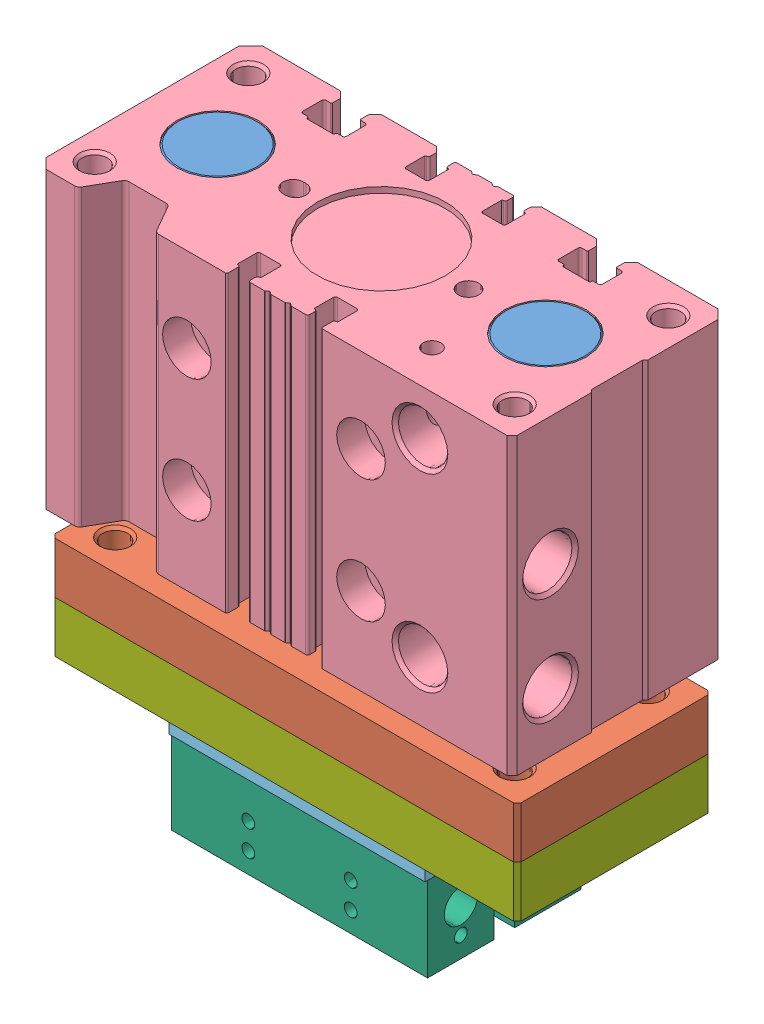
SolidWorks assembly SEALER, configuration Default. Lengths in mm.
Overall size (93 107 42).
11 component instances, 7 part files, 19 mates.
Components (placement in the parent):
- MTCM-25X20-S-T.stp-1: MTCM-25X20-S-T.stp [Default] at (46.5 -57.5 21) x (0 1 0) z (1 0 0) size (73.5 42 93)
  - MTCM-25X20-S-T-0_guide_shaft.stp-1: MTCM-25X20-S-T-0_guide_shaft.stp [Default] at (-8 0 32) size (72.56 16 16)
  - MTCM-25X20-S-T-0_guide_shaft.stp-2: MTCM-25X20-S-T-0_guide_shaft.stp [Default] at (-8 0 -32) size (72.56 16 16)
  - MTCM-25X20-S-T_plate.stp-1: MTCM-25X20-S-T_plate.stp [Default] at (-6 0 0) size (10 38 91)
  - MTCM-25X20-S-T-0_guide_rod.stp-1: MTCM-25X20-S-T-0_guide_rod.stp [Default] at (-8 0 0) size (68.06 25 25)
  - MTCM-25X20-S-T-0_body.stp-1: MTCM-25X20-S-T-0_body.stp [Default] at origin size (57.5 42 93)
- INSULATION-1: INSULATION [Default] at (46 -86 30) x (1 0 0) z (0 -1 0) size (50 14 5)
- INSULATION-2: INSULATION [Default] at (46 -86 13) x (1 0 0) z (0 -1 0) size (50 14 5)
- HEATER-1: HEATER [Default] at (46 -96.75 13) x (-1 0 0) z (0 0 -1) size (50 18.5 13)
- HEATER-2: HEATER [Default] at (46 -96.75 30) size (50 18.5 13)
- Mounting plate-1: Mounting plate [Default] at (93 -73.5 42) x (-1 0 0) z (0 -1 0) size (91 38 10)
Mates (geometry in assembly coordinates):
- Concentric81: concentric anti-aligned: cylinder of INSULATION-2 through (56 -88.5 13) axis (0 -1 0) radius 1.65; cylinder of HEATER-1 through (56 -88.5 13) axis (0 1 0) radius 1.25
- Coincident90: coincident anti-aligned: plane of INSULATION-2 through (46 -88.5 13) normal (0 -1 0); plane of HEATER-1 through (71 -88.5 6.5) normal (0 1 0)
- Concentric82: concentric anti-aligned: cylinder of INSULATION-1 through (36 -88.5 30) axis (0 -1 0) radius 1.65; cylinder of HEATER-2 through (36 -88.5 30) axis (0 1 0) radius 1.25
- Concentric83: concentric anti-aligned: cylinder of INSULATION-1 through (56 -88.5 30) axis (0 -1 0) radius 1.65; cylinder of HEATER-2 through (56 -88.5 30) axis (0 1 0) radius 1.25
- Coincident91: coincident anti-aligned: plane of INSULATION-1 through (46 -88.5 30) normal (0 -1 0); plane of HEATER-2 through (21 -88.5 36.5) normal (0 1 0)
- Parallel2: parallel aligned: plane of INSULATION-2 through (21 -88.5 6) normal (0 0 -1); plane of HEATER-1 through (46 -96.75 6.5) normal (0 0 -1)
- Coincident95: coincident aligned: plane of INSULATION-1 through (71 -88.5 23) normal (1 0 0); plane of INSULATION-2 through (71 -88.5 6) normal (1 0 0)
- Coincident96: coincident aligned: plane of MTCM-25X20-S-T.stp-1/MTCM-25X20-S-T-0_body.stp-1 through (74.45 0 2.8) normal (0 1 0)
- Coincident97: coincident anti-aligned: plane of MTCM-25X20-S-T.stp-1/MTCM-25X20-S-T-0_body.stp-1 through (17.45 0 0) normal (0 0 -1)
- Coincident98: coincident anti-aligned: plane of MTCM-25X20-S-T.stp-1/MTCM-25X20-S-T-0_body.stp-1 through (0 0 2.3) normal (-1 0 0)
- Coincident101: coincident aligned: plane of INSULATION-1 through (21 -88.5 23) normal (-1 0 0); plane of INSULATION-2 through (21 -88.5 6) normal (-1 0 0)
- Distance1: distance = 3 mm anti-aligned: plane of INSULATION-2 through (21 -88.5 20) normal (0 0 1); plane of INSULATION-1 through (21 -88.5 23) normal (0 0 -1)
- Coincident105: coincident: point of INSULATION-1; line of INSULATION-2 through (21 -83.5 20) axis (0 0 -1)
- Coincident110: coincident anti-aligned: plane of MTCM-25X20-S-T.stp-1/MTCM-25X20-S-T_plate.stp-1 through (46.5 -73.5 21) normal (0 -1 0); plane of Mounting plate-1 through (93 -73.5 42) normal (0 1 0)
- Coincident111: coincident aligned: plane of MTCM-25X20-S-T.stp-1/MTCM-25X20-S-T_plate.stp-1 through (92 -73.5 39.24) normal (1 0 0); plane of Mounting plate-1 through (92 -83.5 2.76) normal (1 0 0)
- Coincident112: coincident aligned: plane of MTCM-25X20-S-T.stp-1/MTCM-25X20-S-T_plate.stp-1 through (1.76 -73.5 40) normal (0 0 1); plane of Mounting plate-1 through (91.24 -83.5 40) normal (0 0 1)
- Concentric85: concentric anti-aligned: cylinder of INSULATION-1 through (36 -88.5 30) axis (0 -1 0) radius 1.65; cylinder of Mounting plate-1 through (36 -73.5 30) axis (0 1 0) radius 2.25
- Concentric86: concentric anti-aligned: cylinder of INSULATION-1 through (56 -88.5 30) axis (0 -1 0) radius 1.65; cylinder of Mounting plate-1 through (56 -73.5 30) axis (0 1 0) radius 2.25
- Coincident114: coincident anti-aligned: plane of INSULATION-1 through (46 -83.5 30) normal (0 1 0); plane of Mounting plate-1 through (93 -83.5 42) normal (0 -1 0)
